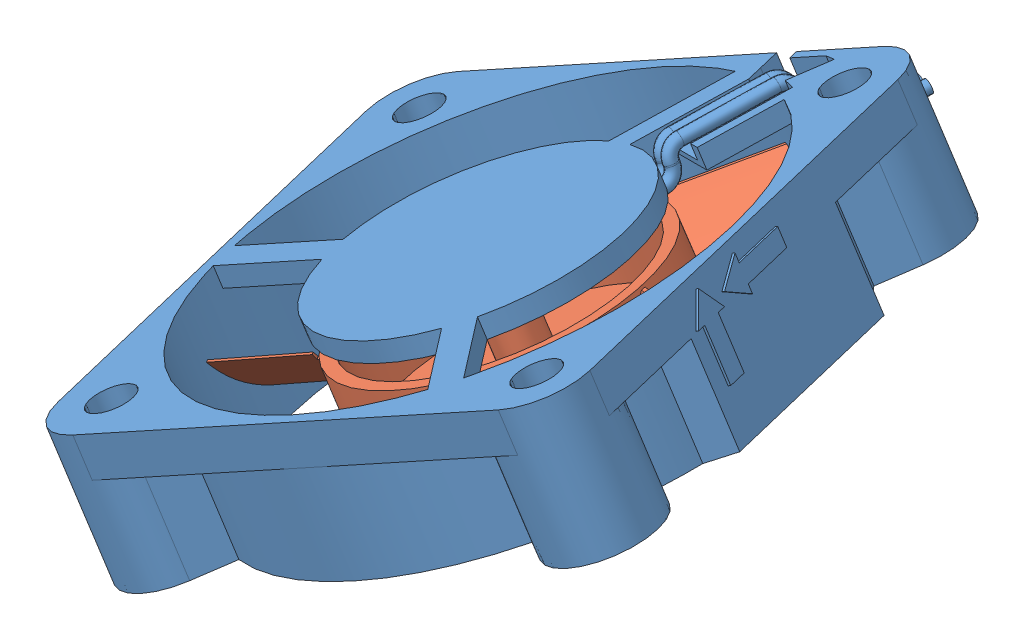
SolidWorks assembly 40x40x10 fan cooler 5v sunon, configuration Default. Lengths in mm.
Overall size (49.46 30.29 52.98).
2 component instances, 2 part files, 2 mates.
Components (placement in the parent):
- 40x40x10-1: 40x40x10 [Default] at (15.2384 13.7872 50.2788) x (-0.206381 0.038763 -0.977704) z (-0.893411 -0.414952 0.172137) size (44.65 10.7 40.2)
- blade-1: blade [Default] at (16.5552 10.7874 49.8819) x (-0.338768 -0.268033 0.901884) z (0.852064 0.319133 0.414898) size (37.1 8.47 37.1)
Mates (geometry in assembly coordinates):
- Concentric1: concentric aligned: cylinder of 40x40x10-1 through (18.2311 6.9695 49.3768) axis (-0.399027 0.909017 0.120269) radius 0.75; cylinder of blade-1 through (30.6345 -21.2866 45.6383) axis (-0.399027 0.909017 0.120269) radius 0.75
- Distance1: distance = 1.8 mm anti-aligned: plane of blade-1 through (16.5552 10.7874 49.8819) normal (-0.399027 0.909017 0.120269); plane of 40x40x10-1 through (15.8369 12.4236 50.0984) normal (0.399027 -0.909017 -0.120269)
